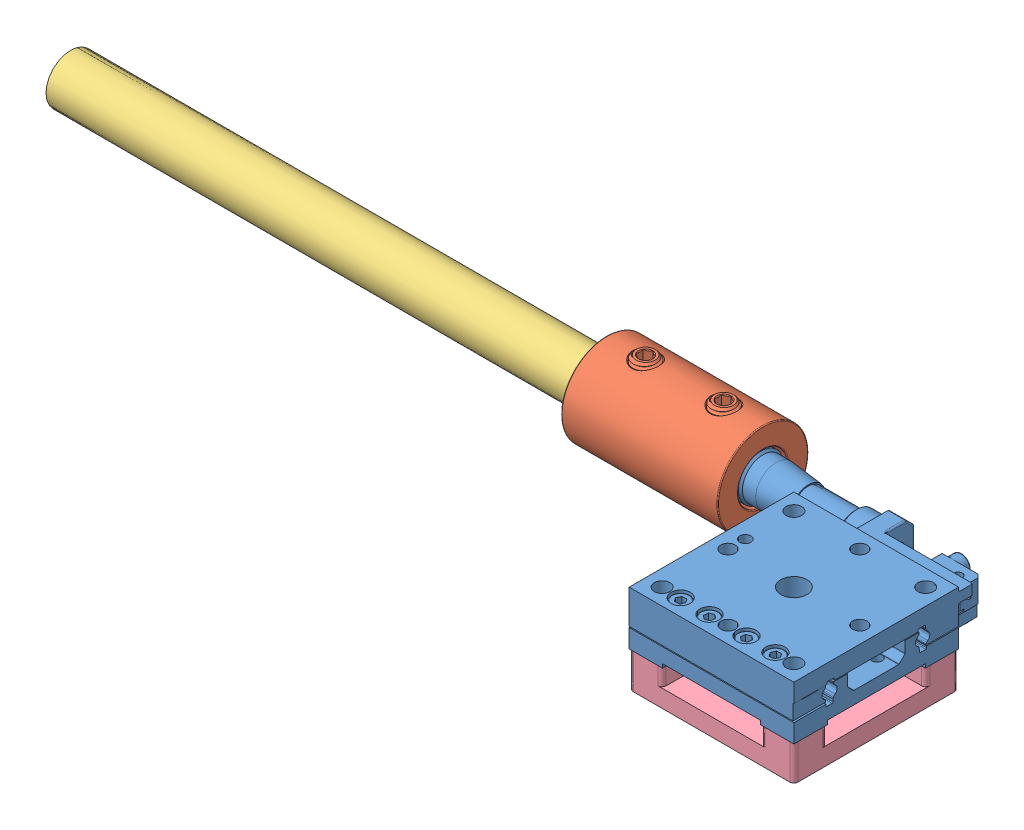
SolidWorks assembly SDS40Extender, configuration Default. Lengths in mm.
Overall size (234.6 59.3 71.52).
5 component instances, 5 part files, 12 mates.
Components (placement in the parent):
- SDS40-1: SDS40 [Default] at (-36.7156 -38.2696 -63.215) x (-0.932566 0.315914 -0.174696) z (-0.191501 -0.022695 0.98123) size (76.01 35.86 56.37)
- 5395T413_SET SCREW RIGID SHAFT COUPLING-1: 5395T413_SET SCREW RIGID SHAFT COUPLING [5395T413] at (-72.4 6.2 -45.9) x (0 0 -1) z (1 0 0) size (22 23.1 38)
- 12mmShaft-1: 12mmShaft [Default] at (-373.9 6.2 -45.9) x (0 0 -1) z (0 -1 0) size (12 152.4 12)
- RS4P8E-Solidworks-1: RS4P8E-Solidworks [Default] at (-20 -59.3 -20) size (31.75 101.6 31.75) (hidden)
- DemoBenchAdapter-1: DemoBenchAdapter [Default] at (-40 -8.5 0) size (40 8.5 40)
Mates (geometry in assembly coordinates):
- Coincident1: coincident anti-aligned: plane of SDS40-1 through (-41 0 -52) normal (0 -1 0); plane of assembly through (0 0 0) normal (0 1 0)
- Coincident2: coincident aligned: plane of SDS40-1 through (-40 4.75 0) normal (0 0 1); plane of assembly through (0 0 0) normal (0 0 1)
- Coincident3: coincident aligned: plane of SDS40-1 through (0 -8 -43.3) normal (1 0 0); plane of assembly through (0 0 0) normal (1 0 0)
- Coincident4: coincident anti-aligned: circle of SDS40-1; plane of 5395T413_SET SCREW RIGID SHAFT COUPLING-1 through (-53.4 6.2 -45.9) normal (1 0 0)
- Concentric1: concentric aligned: cylinder of SDS40-1 through (-84.1302 6.2 -45.9) axis (-1 0 0) radius 5.5; circle of 5395T413_SET SCREW RIGID SHAFT COUPLING-1
- Coincident5: coincident anti-aligned: plane of SDS40-1 through (-69.1 6.2 -45.9) normal (-1 0 0); plane of 12mmShaft-1 through (-69.1 6.2 -45.9) normal (1 0 0)
- Concentric2: concentric aligned: cylinder of 5395T413_SET SCREW RIGID SHAFT COUPLING-1 through (-53.4 6.2 -45.9) axis (-1 0 0) radius 6; cylinder of 12mmShaft-1 through (-69.1 6.2 -45.9) axis (-1 0 0) radius 6
- Concentric3: concentric aligned: circle of RS4P8E-Solidworks-1; circle of DemoBenchAdapter-1
- Coincident6: coincident: plane of RS4P8E-Solidworks-1 through (-14.92 -8.5 -20) normal (0 1 0); plane of DemoBenchAdapter-1 through (-40 -8.5 0) normal (0 -1 0)
- Coincident7: coincident aligned: plane of SDS40-1 through (0 0 -49.4) normal (1 0 0); plane of DemoBenchAdapter-1 through (0 0 0) normal (1 0 0)
- Coincident8: coincident aligned: plane of SDS40-1 through (-40 4.75 0) normal (0 0 1); plane of DemoBenchAdapter-1 through (-40 0 0) normal (0 0 1)
- Coincident9: coincident anti-aligned: plane of SDS40-1 through (-41 0 -52) normal (0 -1 0); plane of DemoBenchAdapter-1 through (-40 0 0) normal (0 1 0)
